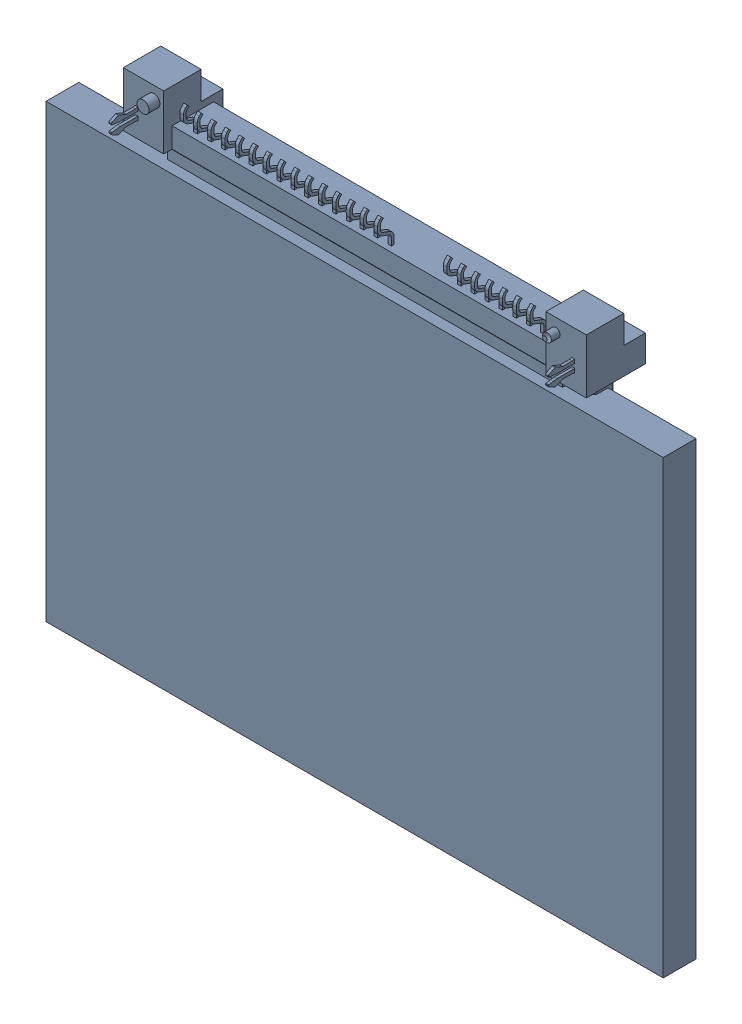
SolidWorks assembly SATA1, configuration Default. Lengths in mm.
Overall size (56.51 47.45 7.82).
3 component instances, 2 part files, 0 mates.
Components (placement in the parent):
- FCI-1: FCI [Default] at (97.1448 42.45 -3.8024) x (-1 0 0) z (0 0 1) size (42.4 12.4 7.82)
- 402660240-1: 402660240 [Default] at (97.1575 20.6375 -4.1024) size (56.52 41.27 3)
  - Extruded_26-1: Extruded_26 [Default] at origin size (56.52 41.27 3)
